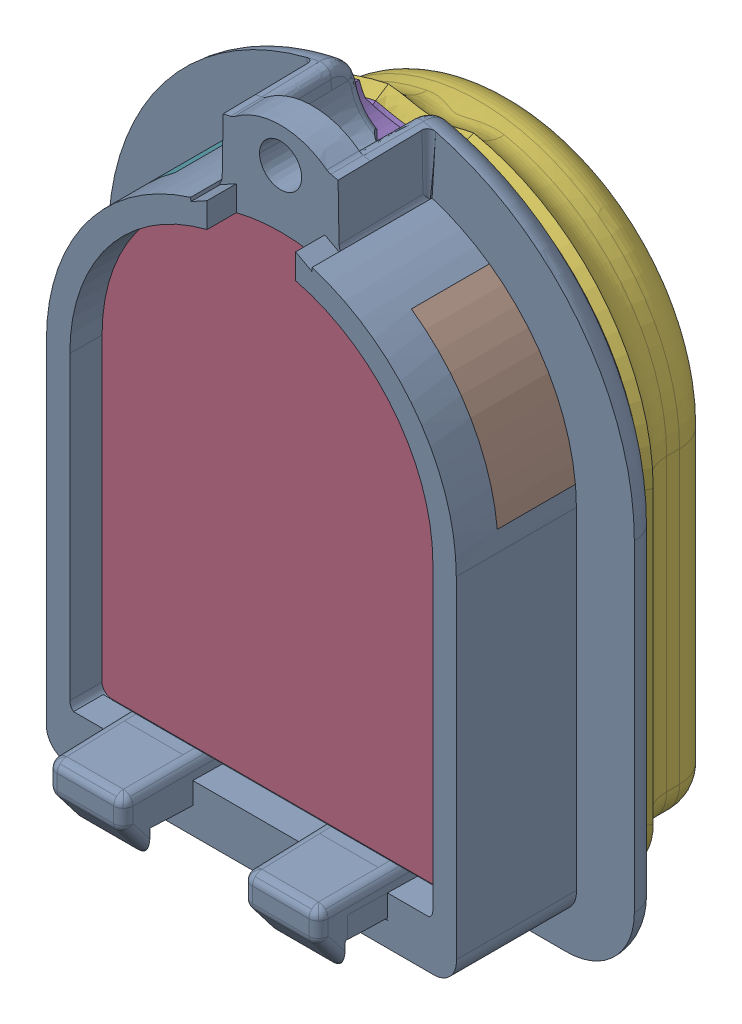
SolidWorks assembly ContinuousDesign, configuration 默认. Lengths in mm.
Overall size (26.95 34.26 17.16).
8 component instances, 7 part files, 21 mates.
Components (placement in the parent):
- Tip1-1: Tip1 [默认] at (-1.9035 7.7463 -5.5591) size (26.95 34.26 11.2)
- lensnew-1: lensnew [默认] at (-1.9035 7.7463 -5.5591) size (18.6 25.2 6)
- Skin0.2-1: Skin0.2 [默认] at (-1.9035 7.4963 -5.5591) x (-1 0 0) z (0 0 -1) size (23.9 30.06 5.2)
- Skin1-1: Skin1 [默认] at (-1.9035 7.4963 -5.5591) x (-1 0 0) z (0 0 -1) size (22.77 29.32 5.25)
- sidelens1-1: sidelens1 [默认] at (-1.9035 7.7463 -6.2091) size (6.4 7.71 4)
- sidelens1-2: sidelens1 [默认] at (-1.9035 7.7463 2.0909) x (-1 0 0) z (0 0 -1) size (6.4 7.71 4)
- bottomlens-1: bottomlens [默认] at (-5.9035 -10.5037 0.4409) x (1 0 0) z (0 1 0) size (8 4.5 2.35)
- continuousMarker-1: continuousMarker [默认] at (-9.1535 -5.7162 -10.7591) size (15.5 20.5 0.4)
Mates (geometry in assembly coordinates):
- 同心1: concentric aligned: cylinder of Tip1-1 through (-1.9035 7.7463 51.2878) axis (0 0 -1) radius 9.3; cylinder of lensnew-1 through (-1.9035 7.7463 0.4409) axis (0 0 -1) radius 9.3
- 重合1: coincident anti-aligned: plane of Tip1-1 through (-1.9035 -8.1537 51.2878) normal (0 1 0); plane of lensnew-1 through (-11.2035 -8.1537 0.4409) normal (0 -1 0)
- 重合2: coincident aligned: plane of Tip1-1 through (-1.964 4.3089 -5.5591) normal (0 0 -1); plane of lensnew-1 through (-1.9035 7.7463 -5.5591) normal (0 0 -1)
- 重合3: coincident anti-aligned: plane of lensnew-1 through (-1.9035 7.7463 -5.5591) normal (0 0 -1); plane of Skin0.2-1 through (-1.9035 7.4963 -5.5591) normal (0 0 1)
- 同心2: concentric aligned: cone of Tip1-1 through (-1.9035 19.9963 -1.0591) axis (0 0 1); cylinder of Skin0.2-1 through (-1.9035 19.9963 -6.3091) axis (0 0 1) radius 2.75
- 宽度1: width aligned: plane of Skin0.2-1 through (-13.8535 7.4963 -5.5591) normal (-1 0 0); plane of Skin0.2-1 through (10.0465 7.4963 -5.5591) normal (1 0 0); plane of Tip1-1 through (-12.4035 7.7463 2.0909) normal (-1 0 0); plane of Tip1-1 through (8.5965 7.7463 2.0909) normal (1 0 0)
- 重合4: coincident anti-aligned: plane of Skin0.2-1 through (-1.9035 7.4963 -10.7591) normal (0 0 -1); plane of Skin1-1 through (-1.9035 7.4963 -10.7591) normal (0 0 1)
- 宽度2: width anti-aligned: plane of Skin0.2-1 through (-13.8535 7.4963 -5.5591) normal (-1 0 0); plane of Skin0.2-1 through (10.0465 7.4963 -5.5591) normal (1 0 0); plane of Skin1-1 through (-12.8325 0.0508 -6.2245) normal (-0.891007 0 0.45399); plane of Skin1-1 through (9.0255 0.0508 -6.2245) normal (0.891007 0 0.45399)
- 重合5: coincident aligned: cone of Skin0.2-1 through (-1.9035 7.4963 -6.2245) axis (0 0 1); cone of Skin1-1 through (-1.9035 7.4963 -6.2245) axis (0 0 1)
- 重合6: coincident anti-aligned: plane of Tip1-1 through (-16.7251 9.2061 -4.0591) normal (0.104528 0.994522 0); plane of sidelens1-1 through (8.4147 6.5638 -0.0591) normal (-0.104528 -0.994522 0)
- 重合7: coincident anti-aligned: plane of Tip1-1 through (-1.9035 7.7463 -4.0591) normal (0 0 1); plane of sidelens1-1 through (8.4147 6.5638 -4.0591) normal (0 0 -1)
- 同心3: concentric aligned: cylinder of Tip1-1 through (-1.9035 7.7463 2.0909) axis (0 0 -1) radius 10.5; cylinder of sidelens1-1 through (-1.9035 7.7463 -0.0591) axis (0 0 -1) radius 10.5
- 同心4: concentric anti-aligned: cylinder of Tip1-1 through (-1.9035 7.7463 2.0909) axis (0 0 -1) radius 10.5; cylinder of sidelens1-2 through (-1.9035 7.7463 -4.0591) axis (0 0 1) radius 10.5
- 重合8: coincident anti-aligned: plane of Tip1-1 through (12.0819 17.1622 -0.0591) normal (0.104528 -0.994522 0); plane of sidelens1-2 through (-13.0579 14.5199 -4.0591) normal (-0.104528 0.994522 0)
- 重合9: coincident anti-aligned: plane of Tip1-1 through (-1.9035 7.7463 -4.0591) normal (0 0 1); plane of sidelens1-2 through (-1.9035 7.7463 -4.0591) normal (0 0 -1)
- 重合10: coincident anti-aligned: plane of lensnew-1 through (-11.2035 -8.1537 0.4409) normal (0 -1 0); plane of bottomlens-1 through (-5.9035 -8.1537 0.4409) normal (0 1 0)
- 重合11: coincident anti-aligned: plane of Tip1-1 through (-5.9035 -18.1537 0.4409) normal (0 0 -1); plane of bottomlens-1 through (-5.9035 -8.1537 0.4409) normal (0 0 1)
- 重合12: coincident anti-aligned: plane of Tip1-1 through (2.0965 -18.1537 0.4409) normal (-1 0 0); plane of bottomlens-1 through (2.0965 -8.1537 0.4409) normal (1 0 0)
- 距离1: distance = 7 mm: line of continuousMarker-1 through (-9.6535 -5.7162 -10.7591) axis (1 0 0); line of Skin0.2-1 through (-11.7809 -10.9037 -6.0591) axis (1 0 0)
- 重合14: coincident aligned: plane of Skin0.2-1 through (-1.9035 7.4963 -10.7591) normal (0 0 -1); plane of continuousMarker-1 through (-9.1535 -5.7162 -10.7591) normal (0 0 -1)
- 宽度3: width aligned: plane of Tip1-1 through (-12.4035 7.7463 2.0909) normal (-1 0 0); plane of Tip1-1 through (8.5965 7.7463 2.0909) normal (1 0 0); plane of continuousMarker-1 through (-9.6535 5.2689 -10.7591) normal (-1 0 0); plane of continuousMarker-1 through (5.8465 -5.7162 -10.3591) normal (1 0 0)
